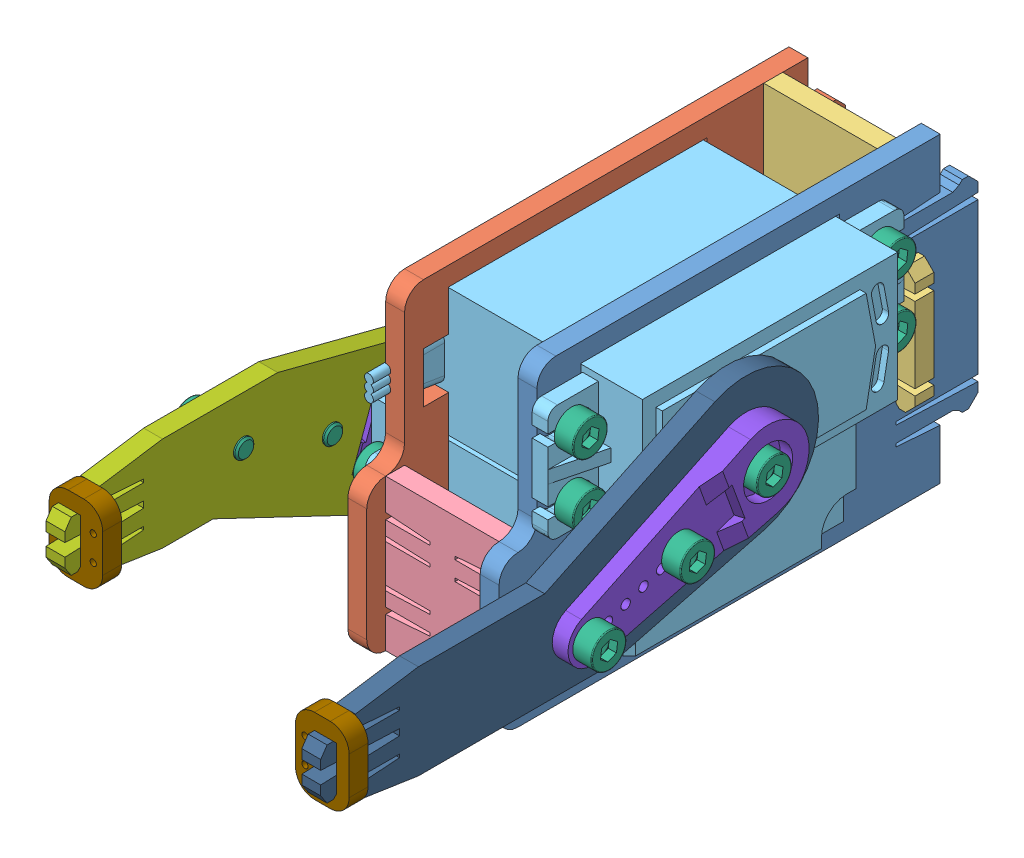
SolidWorks assembly eyebrow, configuration Default. Lengths in mm.
Overall size (66.6 48 120.1).
26 component instances, 10 part files, 50 mates.
Components (placement in the parent):
- eyebrow-frame-1-1: eyebrow-frame-1 [Default] at origin size (3 48 76)
- eyebrow-frame-2-1: eyebrow-frame-2 [Default] at origin size (3 48 76)
- eyebrow-frame-3-1: eyebrow-frame-3 [Default] at origin size (30 48 3)
- eyebrow-frame-4-1: eyebrow-frame-4 [Default] at origin size (30 24.57 3)
- servo-standard-1: servo-standard [Default] at (-14.9 10.5 0) x (0 0 -1) z (0 -1 0) size (58.5 43.2 20.3)
- servo-standard-2: servo-standard [Default] at (14.9 -10.5 0) x (0 0 -1) z (0 1 0) size (58.5 43.2 20.3)
- socket head cap screw_iso-1: socket head cap screw_iso [ISO 4762 M3 x 6 --- 6N] at (17.5 15.5 24.5) x (-1 0 0) z (0 -0.924225 -0.381849) size (9 5.5 5.5)
- socket head cap screw_iso-2: socket head cap screw_iso [ISO 4762 M3 x 6 --- 6N] at (17.5 5.5 24.5) x (-1 0 0) z (0 -0.924225 -0.381849) size (9 5.5 5.5)
- socket head cap screw_iso-3: socket head cap screw_iso [ISO 4762 M3 x 6 --- 6N] at (17.5 15.5 -24.5) x (-1 0 0) z (0 -0.924225 -0.381849) size (9 5.5 5.5)
- socket head cap screw_iso-4: socket head cap screw_iso [ISO 4762 M3 x 6 --- 6N] at (17.5 5.5 -24.5) x (-1 0 0) z (0 -0.924225 -0.381849) size (9 5.5 5.5)
- socket head cap screw_iso-5: socket head cap screw_iso [ISO 4762 M3 x 6 --- 6N] at (-17.5 -5.5 24.5) size (9 5.5 5.5)
- socket head cap screw_iso-6: socket head cap screw_iso [ISO 4762 M3 x 6 --- 6N] at (-17.5 -15.5 24.5) size (9 5.5 5.5)
- socket head cap screw_iso-7: socket head cap screw_iso [ISO 4762 M3 x 6 --- 6N] at (-17.5 -5.5 -24.5) size (9 5.5 5.5)
- socket head cap screw_iso-8: socket head cap screw_iso [ISO 4762 M3 x 6 --- 6N] at (-17.5 -15.5 -24.5) size (9 5.5 5.5)
- lever-outer-towerpro-horn-1: lever-outer-towerpro-horn [Default] at (-27.8 -10.5 10.1) x (0 0 1) z (0 -1 0) size (67 3 29)
- servo-horn-towerpro-1-arm-1: servo-horn-towerpro-1-arm [Default] at (-29.05 -10.5 10.1) x (0 -0.939693 0.34202) z (0 -0.34202 -0.939693) size (13 6.5 39)
- socket head cap screw_iso-19: socket head cap screw_iso [ISO 4762 M3 x 6 --- 6N] at (-33.3 -5.7117 23.2557) size (9 5.5 5.5)
- socket head cap screw_iso-20: socket head cap screw_iso [ISO 4762 M3 x 6 --- 6N] at (-33.3 -0.5814 37.3511) size (9 5.5 5.5)
- textile-snap-4: textile-snap [Default] at (-25.55 -0.5 61.6) x (1 0 0) z (0 -1 0) size (8.5 3 12)
- socket head cap screw_iso-21: socket head cap screw_iso [ISO 4762 M3 x 6 --- 6N] at (-32.3 -10.5 10.1) size (9 5.5 5.5)
- lever-inner-towerpro-horn-1: lever-inner-towerpro-horn [Default] at (27.8 10.5 10.1) x (0 0 1) z (0 1 0) size (79 3 29)
- servo-horn-towerpro-1-arm-2: servo-horn-towerpro-1-arm [Default] at (29.05 10.5 10.1) x (0 0.939693 0.34202) z (0 0.34202 -0.939693) size (13 6.5 39)
- textile-snap-5: textile-snap [Default] at (25.55 0.5 73.6) x (-1 0 0) z (0 1 0) size (8.5 3 12)
- socket head cap screw_iso-22: socket head cap screw_iso [ISO 4762 M3 x 6 --- 6N] at (33.3 0.5814 37.3511) x (-1 0 0) z (0 -0.924225 -0.381849) size (9 5.5 5.5)
- socket head cap screw_iso-23: socket head cap screw_iso [ISO 4762 M3 x 6 --- 6N] at (33.3 5.7117 23.2557) x (-1 0 0) z (0 -0.924225 -0.381849) size (9 5.5 5.5)
- socket head cap screw_iso-24: socket head cap screw_iso [ISO 4762 M3 x 6 --- 6N] at (32.3 10.5 10.1) x (-1 0 0) z (0 -0.924225 -0.381849) size (9 5.5 5.5)
Mates (geometry in assembly coordinates):
- Concentric1: concentric: cylinder of eyebrow-frame-1-1 through (12 15.5 24.5) axis (-1 0 0) radius 1.25; point of servo-standard-1
- Concentric2: concentric: cylinder of eyebrow-frame-1-1 through (12 5.5 -24.5) axis (-1 0 0) radius 1.25; point of servo-standard-1
- Coincident4: coincident anti-aligned: plane of eyebrow-frame-1-1 through (12 0 0) normal (1 0 0); plane of servo-standard-1 through (12 10.5 0) normal (-1 0 0)
- Concentric3: concentric: cylinder of eyebrow-frame-2-1 through (-12 -15.5 24.5) axis (1 0 0) radius 1.25; point of servo-standard-2
- Concentric4: concentric: cylinder of eyebrow-frame-2-1 through (-12 -5.5 -24.5) axis (1 0 0) radius 1.25; point of servo-standard-2
- Coincident5: coincident anti-aligned: plane of eyebrow-frame-2-1 through (-12 0 0) normal (-1 0 0); plane of servo-standard-2 through (-12 -10.5 0) normal (1 0 0)
- Concentric5: concentric anti-aligned: cylinder of eyebrow-frame-1-1 through (12 15.5 24.5) axis (-1 0 0) radius 1.25; cylinder of socket head cap screw_iso-1 through (49.25 15.5 24.5) axis (1 0 0) radius 1.5
- Coincident6: coincident anti-aligned: plane of servo-standard-1 through (14.5 10.5 0) normal (1 0 0); plane of socket head cap screw_iso-1 through (14.5 16.5501 21.9584) normal (-1 0 0)
- Concentric6: concentric anti-aligned: cylinder of eyebrow-frame-1-1 through (12 5.5 24.5) axis (-1 0 0) radius 1.25; cylinder of socket head cap screw_iso-2 through (49.25 5.5 24.5) axis (1 0 0) radius 1.5
- Coincident7: coincident anti-aligned: plane of servo-standard-1 through (14.5 10.5 0) normal (1 0 0); plane of socket head cap screw_iso-2 through (14.5 6.5501 21.9584) normal (-1 0 0)
- Concentric7: concentric anti-aligned: cylinder of eyebrow-frame-1-1 through (12 15.5 -24.5) axis (-1 0 0) radius 1.25; cylinder of socket head cap screw_iso-3 through (49.25 15.5 -24.5) axis (1 0 0) radius 1.5
- Coincident8: coincident anti-aligned: plane of servo-standard-1 through (14.5 10.5 0) normal (1 0 0); plane of socket head cap screw_iso-3 through (14.5 16.5501 -27.0416) normal (-1 0 0)
- Concentric8: concentric anti-aligned: cylinder of eyebrow-frame-1-1 through (12 5.5 -24.5) axis (-1 0 0) radius 1.25; cylinder of socket head cap screw_iso-4 through (49.25 5.5 -24.5) axis (1 0 0) radius 1.5
- Coincident9: coincident anti-aligned: plane of servo-standard-1 through (14.5 10.5 0) normal (1 0 0); plane of socket head cap screw_iso-4 through (14.5 6.5501 -27.0416) normal (-1 0 0)
- Concentric9: concentric anti-aligned: cylinder of eyebrow-frame-2-1 through (-12 -5.5 24.5) axis (1 0 0) radius 1.25; cylinder of socket head cap screw_iso-5 through (-49.25 -5.5 24.5) axis (-1 0 0) radius 1.5
- Coincident10: coincident anti-aligned: plane of servo-standard-2 through (-14.5 -10.5 0) normal (-1 0 0); plane of socket head cap screw_iso-5 through (-14.5 -2.75 24.5) normal (1 0 0)
- Concentric10: concentric anti-aligned: cylinder of eyebrow-frame-2-1 through (-12 -15.5 24.5) axis (1 0 0) radius 1.25; cylinder of socket head cap screw_iso-6 through (-49.25 -15.5 24.5) axis (-1 0 0) radius 1.5
- Coincident11: coincident anti-aligned: plane of servo-standard-2 through (-14.5 -10.5 0) normal (-1 0 0); plane of socket head cap screw_iso-6 through (-14.5 -12.75 24.5) normal (1 0 0)
- Concentric11: concentric anti-aligned: cylinder of eyebrow-frame-2-1 through (-12 -5.5 -24.5) axis (1 0 0) radius 1.25; cylinder of socket head cap screw_iso-7 through (-49.25 -5.5 -24.5) axis (-1 0 0) radius 1.5
- Coincident12: coincident anti-aligned: plane of servo-standard-2 through (-14.5 -10.5 0) normal (-1 0 0); plane of socket head cap screw_iso-7 through (-14.5 -2.75 -24.5) normal (1 0 0)
- Concentric12: concentric anti-aligned: cylinder of eyebrow-frame-2-1 through (-12 -15.5 -24.5) axis (1 0 0) radius 1.25; cylinder of socket head cap screw_iso-8 through (-49.25 -15.5 -24.5) axis (-1 0 0) radius 1.5
- Coincident13: coincident anti-aligned: plane of servo-standard-2 through (-14.5 -10.5 0) normal (-1 0 0); plane of socket head cap screw_iso-8 through (-14.5 -12.75 -24.5) normal (1 0 0)
- Concentric31: concentric anti-aligned: cylinder of lever-outer-towerpro-horn-1 through (-24.8 -5.7117 23.2557) axis (-1 0 0) radius 1.25; cylinder of servo-horn-towerpro-1-arm-1 through (-31.3 -5.7117 23.2557) axis (1 0 0) radius 0.75
- Concentric32: concentric anti-aligned: cylinder of lever-outer-towerpro-horn-1 through (-24.8 -0.5814 37.3511) axis (-1 0 0) radius 1.25; cylinder of servo-horn-towerpro-1-arm-1 through (-31.3 -0.5814 37.3511) axis (1 0 0) radius 0.75
- Coincident41: coincident anti-aligned: plane of lever-outer-towerpro-horn-1 through (-27.8 -10.5 10.1) normal (-1 0 0); plane of servo-horn-towerpro-1-arm-1 through (-27.8 7.1935 38.2459) normal (1 0 0)
- Concentric34: concentric anti-aligned: cylinder of servo-horn-towerpro-1-arm-1 through (-31.3 -5.7117 23.2557) axis (1 0 0) radius 0.75; cylinder of socket head cap screw_iso-19 through (-65.05 -5.7117 23.2557) axis (-1 0 0) radius 1.5
- Coincident44: coincident anti-aligned: plane of servo-horn-towerpro-1-arm-1 through (-30.3 7.1935 38.2459) normal (-1 0 0); plane of socket head cap screw_iso-19 through (-30.3 -2.9617 23.2557) normal (1 0 0)
- Concentric35: concentric anti-aligned: cylinder of servo-horn-towerpro-1-arm-1 through (-31.3 -0.5814 37.3511) axis (1 0 0) radius 0.75; cylinder of socket head cap screw_iso-20 through (-65.05 -0.5814 37.3511) axis (-1 0 0) radius 1.5
- Coincident45: coincident anti-aligned: plane of servo-horn-towerpro-1-arm-1 through (-30.3 7.1935 38.2459) normal (-1 0 0); plane of socket head cap screw_iso-20 through (-30.3 2.1686 37.3511) normal (1 0 0)
- Coincident46: coincident anti-aligned: plane of lever-outer-towerpro-horn-1 through (-24.8 -10.5 60.1) normal (0 0 1); plane of textile-snap-4 through (-25.55 -0.5 60.1) normal (0 0 -1)
- Coincident47: coincident anti-aligned: plane of lever-outer-towerpro-horn-1 through (-24.8 -10.5 10.1) normal (1 0 0); plane of textile-snap-4 through (-24.8 2.5 63.1) normal (-1 0 0)
- Coincident48: coincident anti-aligned: plane of lever-outer-towerpro-horn-1 through (-24.8 2.5 10.1) normal (0 1 0); plane of textile-snap-4 through (-27.8 2.5 63.1) normal (0 -1 0)
- Concentric36: concentric aligned: cylinder of servo-standard-2 through (-28.3 -10.5 10.1) axis (1 0 0) radius 3; cylinder of servo-horn-towerpro-1-arm-1 through (-28.3 -10.5 10.1) axis (1 0 0) radius 3
- Coincident49: coincident anti-aligned: plane of servo-standard-2 through (-28.3 -10.5 10.1) normal (-1 0 0); plane of servo-horn-towerpro-1-arm-1 through (-28.3 -10.5 10.1) normal (1 0 0)
- Concentric37: concentric anti-aligned: cylinder of servo-standard-2 through (-28.3 -10.5 10.1) axis (1 0 0) radius 1.1; cylinder of socket head cap screw_iso-21 through (-64.05 -10.5 10.1) axis (-1 0 0) radius 1.5
- Coincident50: coincident anti-aligned: plane of servo-horn-towerpro-1-arm-1 through (-29.3 -10.5 10.1) normal (-1 0 0); plane of socket head cap screw_iso-21 through (-29.3 -7.75 10.1) normal (1 0 0)
- Concentric38: concentric anti-aligned: cylinder of lever-inner-towerpro-horn-1 through (39.7347 5.7117 23.2557) axis (1 0 0) radius 1.25; cylinder of servo-horn-towerpro-1-arm-2 through (46.2347 5.7117 23.2557) axis (-1 0 0) radius 0.75
- Concentric39: concentric anti-aligned: cylinder of lever-inner-towerpro-horn-1 through (39.7347 0.5814 37.3511) axis (1 0 0) radius 1.25; cylinder of servo-horn-towerpro-1-arm-2 through (46.2347 0.5814 37.3511) axis (-1 0 0) radius 0.75
- Coincident51: coincident anti-aligned: plane of lever-inner-towerpro-horn-1 through (42.7347 10.5 10.1) normal (1 0 0); plane of servo-horn-towerpro-1-arm-2 through (42.7347 -7.1935 38.2459) normal (-1 0 0)
- Coincident52: coincident anti-aligned: plane of lever-inner-towerpro-horn-1 through (39.7347 10.5 72.1) normal (0 0 1); plane of textile-snap-5 through (40.4847 0.5 72.1) normal (0 0 -1)
- Coincident53: coincident anti-aligned: plane of lever-inner-towerpro-horn-1 through (39.7347 10.5 10.1) normal (-1 0 0); plane of textile-snap-5 through (39.7347 -2.5 75.1) normal (1 0 0)
- Coincident54: coincident anti-aligned: plane of lever-inner-towerpro-horn-1 through (39.7347 -2.5 10.1) normal (0 -1 0); plane of textile-snap-5 through (42.7347 -2.5 75.1) normal (0 1 0)
- Concentric40: concentric anti-aligned: cylinder of servo-horn-towerpro-1-arm-2 through (46.2347 0.5814 37.3511) axis (-1 0 0) radius 0.75; cylinder of socket head cap screw_iso-22 through (79.9847 0.5814 37.3511) axis (1 0 0) radius 1.5
- Coincident55: coincident anti-aligned: plane of servo-horn-towerpro-1-arm-2 through (45.2347 -7.1935 38.2459) normal (1 0 0); plane of socket head cap screw_iso-22 through (45.2347 1.6315 34.8095) normal (-1 0 0)
- Concentric41: concentric anti-aligned: cylinder of servo-horn-towerpro-1-arm-2 through (46.2347 5.7117 23.2557) axis (-1 0 0) radius 0.75; cylinder of socket head cap screw_iso-23 through (79.9847 5.7117 23.2557) axis (1 0 0) radius 1.5
- Coincident56: coincident anti-aligned: plane of servo-horn-towerpro-1-arm-2 through (45.2347 -7.1935 38.2459) normal (1 0 0); plane of socket head cap screw_iso-23 through (45.2347 6.7618 20.7141) normal (-1 0 0)
- Concentric42: concentric anti-aligned: cylinder of servo-horn-towerpro-1-arm-2 through (46.2347 10.5 10.1) axis (-1 0 0) radius 1.5; cylinder of socket head cap screw_iso-24 through (78.9847 10.5 10.1) axis (1 0 0) radius 1.5
- Coincident57: coincident anti-aligned: plane of servo-horn-towerpro-1-arm-2 through (44.2347 10.5 10.1) normal (1 0 0); plane of socket head cap screw_iso-24 through (44.2347 11.5501 7.5584) normal (-1 0 0)
- Concentric43: concentric aligned: cylinder of servo-standard-1 through (28.3 10.5 10.1) axis (-1 0 0) radius 3; cylinder of servo-horn-towerpro-1-arm-2 through (28.3 10.5 10.1) axis (-1 0 0) radius 3
- Coincident58: coincident anti-aligned: plane of servo-standard-1 through (28.3 10.5 10.1) normal (1 0 0); plane of servo-horn-towerpro-1-arm-2 through (28.3 10.5 10.1) normal (-1 0 0)
